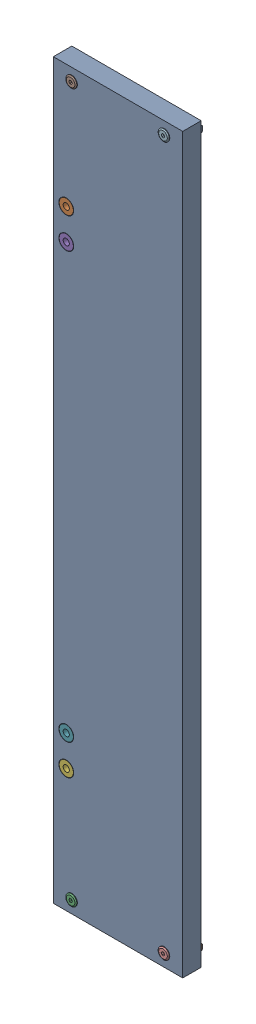
SolidWorks assembly s-assy-leftsmall, configuration ﾃﾞﾌｫﾙﾄ. Lengths in mm.
Overall size (105 595 22).
17 component instances, 4 part files, 6 mates.
Components (placement in the parent):
- plate_left_small-1: plate_left_small [ﾃﾞﾌｫﾙﾄ] at origin size (105 595 15)
- Onimenut_m5-1: Onimenut_m5 [ﾃﾞﾌｫﾙﾄ] at (-42 197.5 2) x (0 0 -1) z (0.999344 0.036204 0) size (13 11.5 11.5)
- s-s-assy-bolt-nut-1: s-s-assy-bolt-nut [ﾃﾞﾌｫﾙﾄ] at (-37.5 -287.5 15) x (0 0 -1) z (1 0 0) size (22 9 17)
  - MISUMI_E-GCBSTSR5-20-1: MISUMI_E-GCBSTSR5-20 [Default] at origin size (21 9 9)
  - MISUMI_HNTP5-5-1: MISUMI_HNTP5-5 [Default] at (16.3 0 0) x (0 0 1) z (0 -1 0) size (17 4.7 8.3)
- Onimenut_m5-2: Onimenut_m5 [ﾃﾞﾌｫﾙﾄ] at (-42 172.5 2) x (0 0 -1) z (0.999344 0.036204 0) size (13 11.5 11.5)
- Onimenut_m5-3: Onimenut_m5 [ﾃﾞﾌｫﾙﾄ] at (-42 -197.5 2) x (0 0 -1) z (-0.999344 0.036204 0) size (13 11.5 11.5)
- Onimenut_m5-4: Onimenut_m5 [ﾃﾞﾌｫﾙﾄ] at (-42 -172.5 2) x (0 0 -1) z (-0.999344 0.036204 0) size (13 11.5 11.5)
- s-s-assy-bolt-nut-2: s-s-assy-bolt-nut [ﾃﾞﾌｫﾙﾄ] at (-37.5 287.5 15) x (0 0 -1) z (1 0 0) size (22 9 17)
  - MISUMI_E-GCBSTSR5-20-1: MISUMI_E-GCBSTSR5-20 [Default] at origin size (21 9 9)
  - MISUMI_HNTP5-5-1: MISUMI_HNTP5-5 [Default] at (16.3 0 0) x (0 0 1) z (0 -1 0) size (17 4.7 8.3)
- s-s-assy-bolt-nut-3: s-s-assy-bolt-nut [ﾃﾞﾌｫﾙﾄ] at (37.5 -287.5 15) x (0 0 -1) z (1 0 0) size (22 9 17)
  - MISUMI_E-GCBSTSR5-20-1: MISUMI_E-GCBSTSR5-20 [Default] at origin size (21 9 9)
  - MISUMI_HNTP5-5-1: MISUMI_HNTP5-5 [Default] at (16.3 0 0) x (0 0 1) z (0 -1 0) size (17 4.7 8.3)
- s-s-assy-bolt-nut-4: s-s-assy-bolt-nut [ﾃﾞﾌｫﾙﾄ] at (37.5 287.5 15) x (0 0 -1) z (1 0 0) size (22 9 17)
  - MISUMI_E-GCBSTSR5-20-1: MISUMI_E-GCBSTSR5-20 [Default] at origin size (21 9 9)
  - MISUMI_HNTP5-5-1: MISUMI_HNTP5-5 [Default] at (16.3 0 0) x (0 0 1) z (0 -1 0) size (17 4.7 8.3)
Mates (geometry in assembly coordinates):
- 一致1: coordinate: point of plate_left_small-1
- 同心円1: concentric anti-aligned: cylinder of plate_left_small-1 through (-42 197.5 0) axis (0 0 1) radius 4; cylinder of Onimenut_m5-1 through (-42 197.5 2) axis (0 0 -1) radius 5.5
- 一致2: coincident anti-aligned: plane of plate_left_small-1 through (-42 197.5 14) normal (0 0 1); plane of Onimenut_m5-1 through (-42 197.5 14) normal (0 0 -1)
- 同心円2: concentric aligned: cylinder of plate_left_small-1 through (-37.5 -287.5 0) axis (0 0 1) radius 2.5; cylinder of s-s-assy-bolt-nut-1/MISUMI_E-GCBSTSR5-20-1 through (-37.5 -287.5 16) axis (0 0 1) radius 2.5
- 一致3: coincident anti-aligned: plane of plate_left_small-1 through (0 0 15) normal (0 0 1); plane of s-s-assy-bolt-nut-1/MISUMI_E-GCBSTSR5-20-1 through (-37.5 -285.245 15) normal (0 0 -1)
- 平行1: parallel aligned: plane of plate_left_small-1 through (-52.5 297.5 15) normal (-1 0 0); plane of s-s-assy-bolt-nut-1/MISUMI_HNTP5-5-1 through (-43.5 -291.45 -2.2) normal (-1 0 0)
